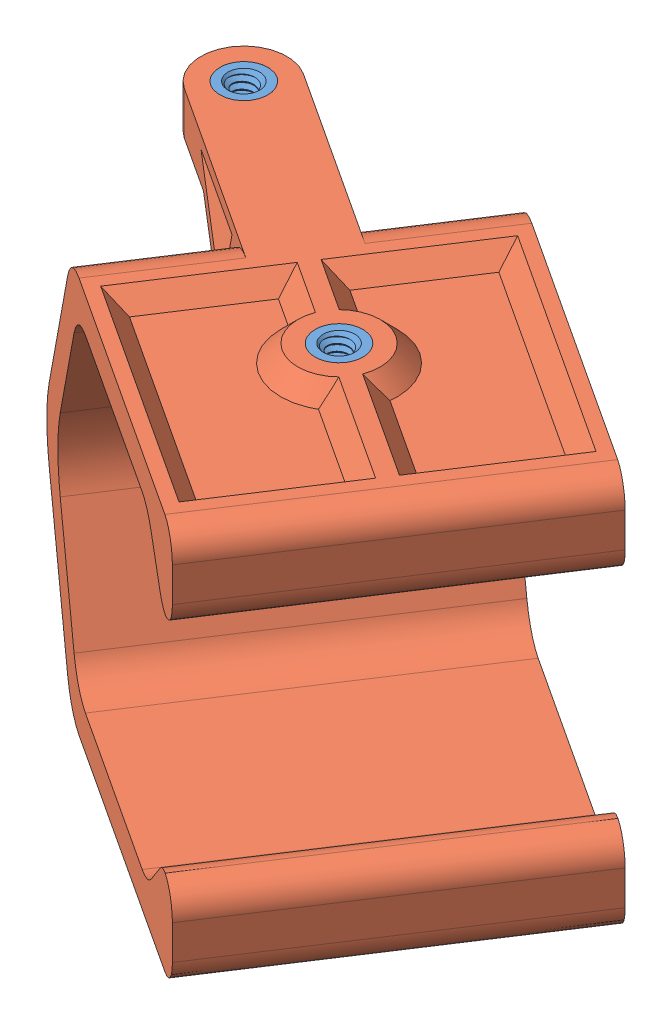
SolidWorks assembly Battery holder_5_2mAH, configuration Default. Lengths in mm.
Overall size (76.87 46.24 68.46).
3 component instances, 2 part files, 4 mates.
Components (placement in the parent):
- 93365A130_HEAT-SET INSERTS FOR PLASTICS-1: 93365A130_HEAT-SET INSERTS FOR PLASTICS [93365A130] at (-76.3232 15.601 30.9695) size (5.56 4.29 5.56)
- battery holder_5_2maH-1: battery holder_5_2maH [Default] at (-54.9027 -7.399 67.6596) x (0 -1 0) z (0.546944 0 -0.837169) size (46 67 38)
- 93365A130_HEAT-SET INSERTS FOR PLASTICS-2: 93365A130_HEAT-SET INSERTS FOR PLASTICS [93365A130] at (-44.4271 15.601 51.8081) size (5.56 4.29 5.56)
Mates (geometry in assembly coordinates):
- Concentric1: concentric aligned: cylinder of 93365A130_HEAT-SET INSERTS FOR PLASTICS-1 through (-76.3232 15.601 30.9695) axis (0 1 0) radius 2.5273; cylinder of battery holder_5_2maH-1 through (-76.3232 -30.4 30.9695) axis (0 1 0) radius 2.2458
- Coincident1: coincident aligned: plane of 93365A130_HEAT-SET INSERTS FOR PLASTICS-1 through (-76.3232 15.601 30.9695) normal (0 1 0); plane of battery holder_5_2maH-1 through (-34.1188 15.601 35.8472) normal (0 1 0)
- Concentric2: concentric aligned: circle of battery holder_5_2maH-1; cylinder of 93365A130_HEAT-SET INSERTS FOR PLASTICS-2 through (-44.4271 15.601 51.8081) axis (0 1 0) radius 2.5273
- Coincident2: coincident aligned: plane of battery holder_5_2maH-1 through (-34.1188 15.601 35.8472) normal (0 1 0); plane of 93365A130_HEAT-SET INSERTS FOR PLASTICS-2 through (-44.4271 15.601 51.8081) normal (0 1 0)
